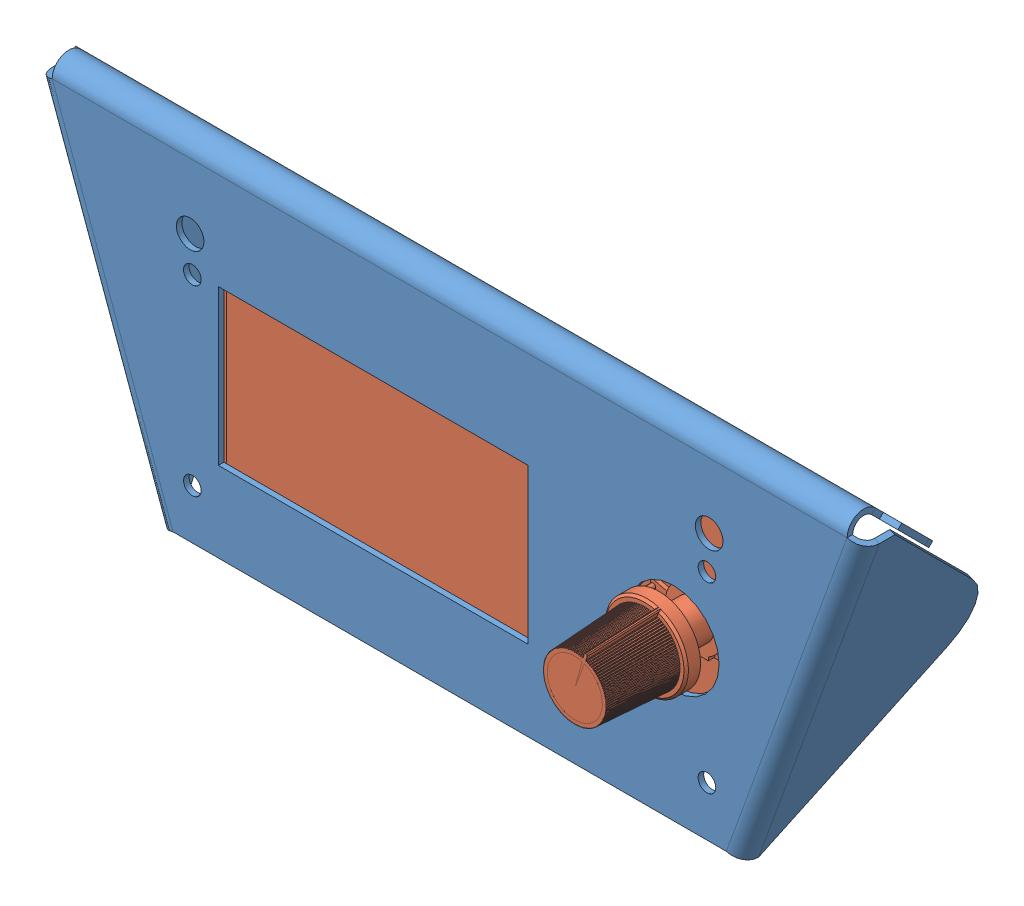
SolidWorks assembly ASM_ecran, configuration Défaut. Lengths in mm.
Overall size (149.31 64.03 48.33).
2 component instances, 2 part files, 3 mates.
Components (placement in the parent):
- eMotronic_ LCD_cover_pliage_r2.0-1: eMotronic_ LCD_cover_pliage_r2.0 [Défaut] at (-132.0658 -22.72 13.3488) size (149.31 64.03 30.7)
- eMotronic_LCD-1: eMotronic_LCD [Défaut] at (-41.4947 -20.0376 8.5488) size (100 40 34.13)
Mates (geometry in assembly coordinates):
- Distance1: distance = 5 mm anti-aligned: plane of eMotronic_LCD-1 through (-81.8158 2.78 9.3488) normal (0 0 1); plane of eMotronic_ LCD_cover_pliage_r2.0-1 through (-132.0658 -22.72 14.3488) normal (0 0 -1)
- Coaxiale1: concentric anti-aligned: cylinder of eMotronic_ LCD_cover_pliage_r2.0-1 through (-128.5658 19.28 15.3488) axis (0 0 1) radius 1.6; cylinder of eMotronic_LCD-1 through (-128.5658 19.28 9.3488) axis (0 0 -1) radius 1.7
- Coaxiale2: concentric anti-aligned: cylinder of eMotronic_ LCD_cover_pliage_r2.0-1 through (-128.5658 -13.72 15.3488) axis (0 0 1) radius 1.6; cylinder of eMotronic_LCD-1 through (-128.5658 -13.72 9.3488) axis (0 0 -1) radius 1.7
